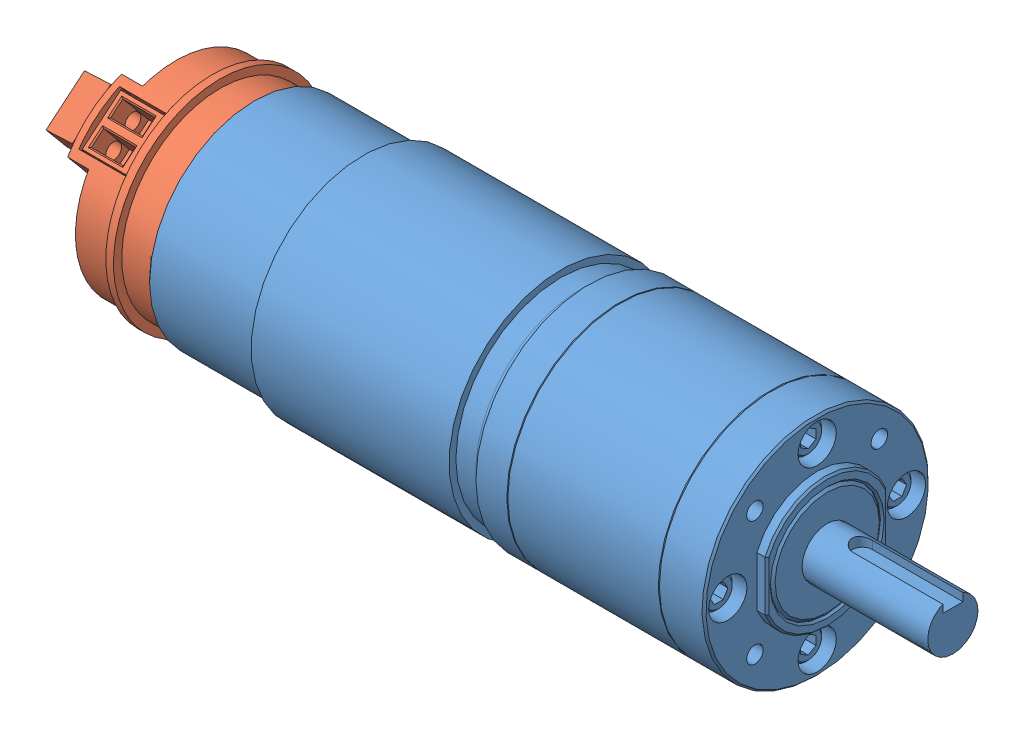
SolidWorks assembly am-2923+PG27+With+Encoder, configuration Default. Lengths in mm.
Overall size (166.09 59.78 59.78).
2 component instances, 2 part files, 0 mates.
Components (placement in the parent):
- PG27 with longer backshaft-1: PG27 with longer backshaft [Default] at (-72.142 14.6319 -3.8624) size (156.55 45 45)
- Hall Effect Encoder for PG Gearboxes-1: Hall Effect Encoder for PG Gearboxes [Default] at (-71.507 14.6319 -3.8624) x (0 0.640339 -0.768093) z (0 0.768093 0.640339) size (42.44 27.83 42.44)
